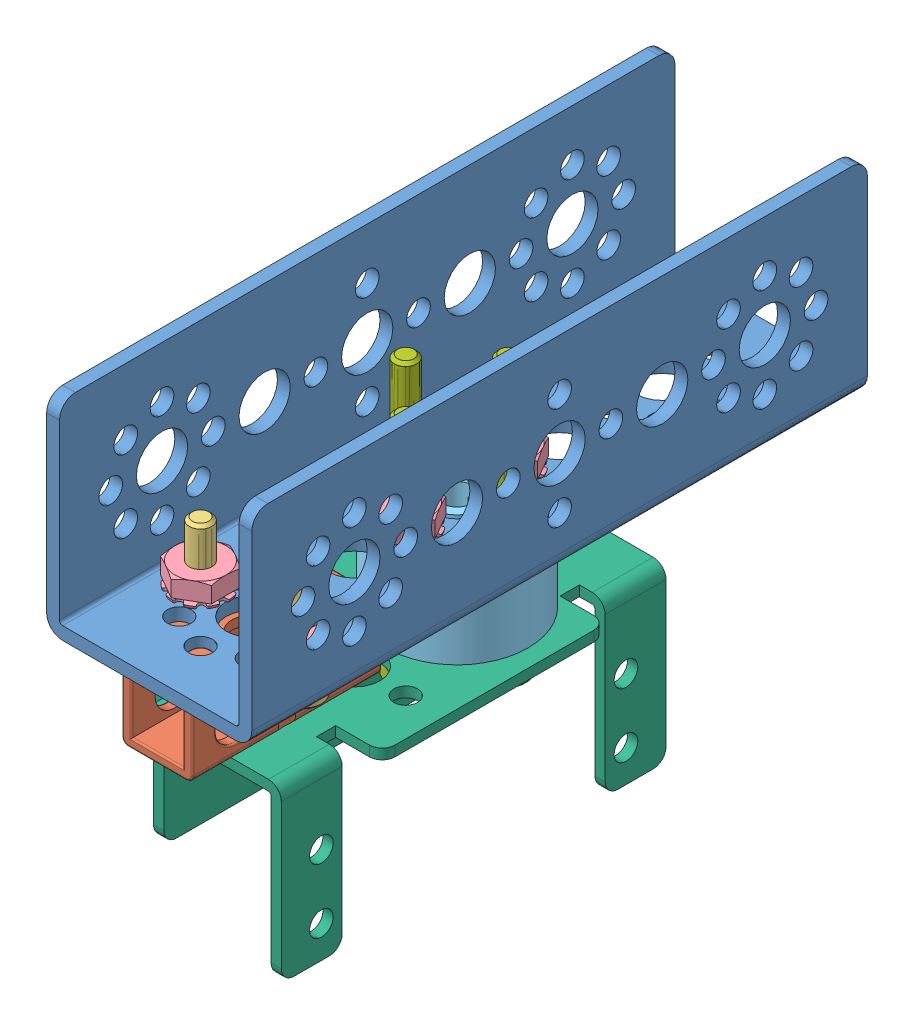
SolidWorks assembly Mantis step 10, configuration Default. Lengths in mm.
Overall size (34.83 71.3 96).
17 component instances, 7 part files, 12 mates.
Components (placement in the parent):
- Mantis step 9-1: Mantis step 9 [Default] at origin size (32 42.5 96)
  - Channel 96mm-1: Channel 96mm [Default] at origin size (32 32 96)
  - LEGO HPC-1: LEGO HPC [Default] at (0 0 32) x (-1 0 0) z (0 0 1) size (24.2 11.25 29.5)
  - Screw SHCS 6-32 x 0.5-1: Screw SHCS 6-32 x 0.5 [PreviewCfg] at (8 -4.7052 32) x (0 1 0) z (0 0 1) size (16.21 5.74 5.74)
  - Screw SHCS 6-32 x 0.5-2: Screw SHCS 6-32 x 0.5 [PreviewCfg] at (-8 -4.7052 32) x (0 1 0) z (0 0 1) size (16.21 5.74 5.74)
  - Nut Hex 6-32 KEP lock-1: Nut Hex 6-32 KEP lock [90675A007] at (-8 4.1828 32) size (8.74 3.59 9.17)
  - Nut Hex 6-32 KEP lock-2: Nut Hex 6-32 KEP lock [90675A007] at (8 4.1828 32) size (8.74 3.59 9.17)
- Hub spacer-1: Hub spacer [Default] x (-1 0 0) z (0 1 0) size (22.2 22.2 17.7)
- Bracket servo single-1: Bracket servo single [Default] at (0 -12.7 8) x (0 0 1) z (1 0 0) size (60 26.6 32.67)
- Screw SHCS 6-32 x 1.250-1: Screw SHCS 6-32 x 1.250 [PreviewCfg] at (-8 -17.8052 0) x (0 1 0) z (0 0 -1) size (35.26 5.74 5.74)
- Nut Hex 6-32 KEP lock-1: Nut Hex 6-32 KEP lock [90675A007] at (-8 4.1828 0) size (8.74 3.59 9.17)
- Nut Hex 6-32 KEP lock-5: Nut Hex 6-32 KEP lock [90675A007] at (0 4.1828 -8) x (0 0 1) z (-1 0 0) size (8.74 3.59 9.17)
- Nut Hex 6-32 KEP lock-6: Nut Hex 6-32 KEP lock [90675A007] at (8 4.1828 0) x (-1 0 0) z (0 0 -1) size (8.74 3.59 9.17)
- Nut Hex 6-32 KEP lock-7: Nut Hex 6-32 KEP lock [90675A007] at (0 4.1828 8) x (0 0 -1) z (1 0 0) size (8.74 3.59 9.17)
- Screw SHCS 6-32 x 1.250-5: Screw SHCS 6-32 x 1.250 [PreviewCfg] at (0 -17.8052 -8) x (0 1 0) z (1 0 0) size (35.26 5.74 5.74)
- Screw SHCS 6-32 x 1.250-6: Screw SHCS 6-32 x 1.250 [PreviewCfg] at (8 -17.8052 0) x (0 1 0) z (0 0 1) size (35.26 5.74 5.74)
- Screw SHCS 6-32 x 1.250-7: Screw SHCS 6-32 x 1.250 [PreviewCfg] at (0 -17.8052 8) x (0 1 0) z (-1 0 0) size (35.26 5.74 5.74)
Mates (geometry in assembly coordinates):
- Concentric1: concentric anti-aligned: cylinder of Hub spacer-1 through (0 -15.2 0) axis (0 1 0) radius 2.45; cylinder of Mantis step 9-1/Channel 96mm-1 through (0 32 0) axis (0 -1 0) radius 4
- Coincident1: coincident anti-aligned: plane of Mantis step 9-1/Channel 96mm-1 through (-13.5 0 48) normal (0 -1 0); plane of Hub spacer-1 through (0 0 0) normal (0 1 0)
- Parallel1: parallel anti-aligned: plane of Hub spacer-1; plane of assembly through (0 0 0) normal (1 0 0)
- Coincident2: coincident anti-aligned: plane of Hub spacer-1 through (0 -12.7 0) normal (0 -1 0); plane of Bracket servo single-1 through (10.6 -12.7 25.5) normal (0 1 0)
- Parallel2: parallel aligned: plane of Bracket servo single-1 through (0 -12.7 8) normal (1 0 0); plane of assembly through (0 0 0) normal (1 0 0)
- Coincident11: coincident aligned: plane of Mantis step 9-1/Channel 96mm-1 through (13.5 2 48) normal (0 1 0); circle of Nut Hex 6-32 KEP lock-1
- Parallel3: parallel aligned: plane of Nut Hex 6-32 KEP lock-1 through (-8 4.1828 0) normal (1 0 0); plane of assembly through (0 0 0) normal (1 0 0)
- Concentric4: concentric: cylinder of Mantis step 9-1/Channel 96mm-1 through (-8 32 0) axis (0 -1 0) radius 1.85; point of Nut Hex 6-32 KEP lock-1
- Concentric5: concentric: cylinder of Mantis step 9-1/Channel 96mm-1 through (-8 32 0) axis (0 -1 0) radius 1.85; point of Screw SHCS 6-32 x 1.250-1
- Parallel4: parallel anti-aligned: plane of Screw SHCS 6-32 x 1.250-1 through (-8 -17.8052 0) normal (0 0 -1); plane of assembly through (0 0 0) normal (0 0 1)
- Coincident17: coincident anti-aligned: plane of Bracket servo single-1 through (10.6 -14.3 25.5) normal (0 -1 0); plane of Screw SHCS 6-32 x 1.250-1 through (-5.1298 -14.3 0) normal (0 1 0)
- Concentric6: concentric anti-aligned: cylinder of Hub spacer-1 through (0 -15.2 0) axis (0 1 0) radius 3.95; cylinder of Bracket servo single-1 through (0 -12.7 0) axis (0 -1 0) radius 4
